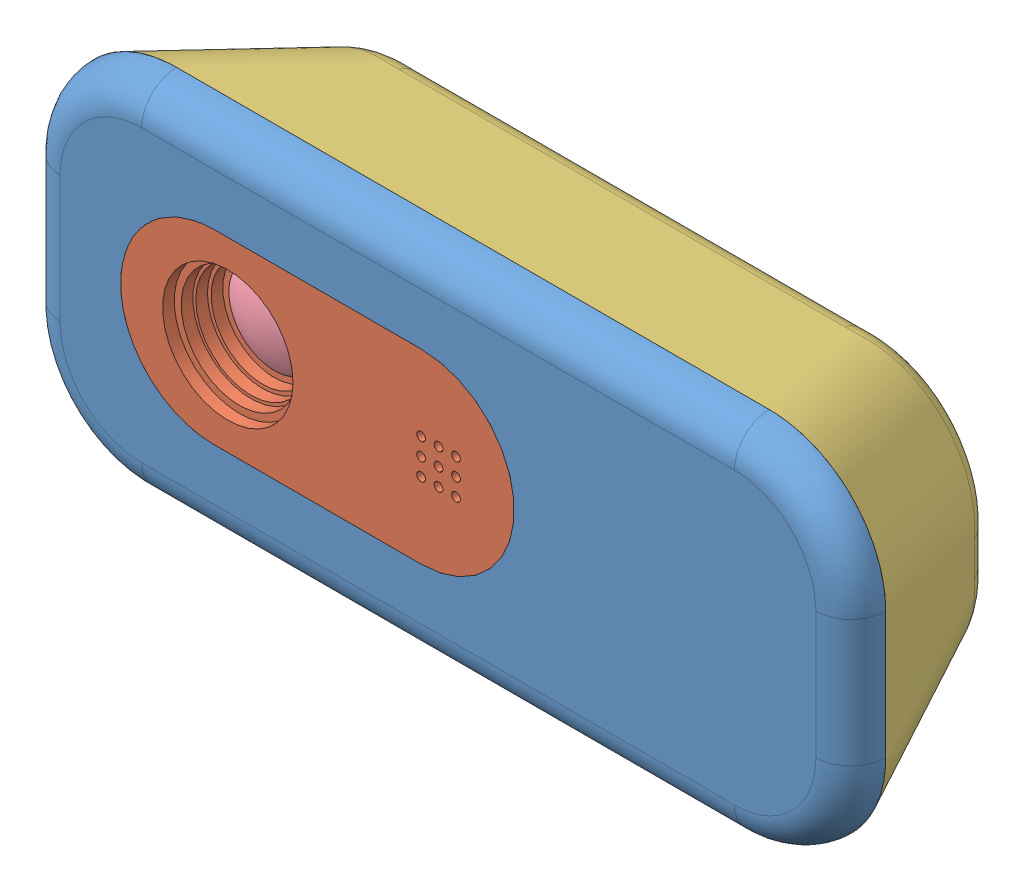
SolidWorks assembly webcam, configuration Default. Lengths in mm.
Overall size (72.03 32.03 23.6).
5 component instances, 5 part files, 0 mates.
Components (placement in the parent):
- Front-1: Front [Default] at origin size (70.9 30.9 3)
- camera_1-1: camera_1 [Default] at (-10.35 0 -3.5) size (33.8 16 5)
- housing-1: housing [Default] at (0 0 -1.5) x (-1 0 0) z (0 0 -1) size (72.03 32.03 21.42)
- lens-1: lens [Default] at (-18.05 0 -2) x (0 0 1) z (-1 0 0) size (1.93 8.24 8.32)
- camera_2-1: camera_2 [Default] at (-18.05 0 -3.4) x (0.927559 0.373676 0) z (0 0 1) size (7.8 7.8 0.9)
